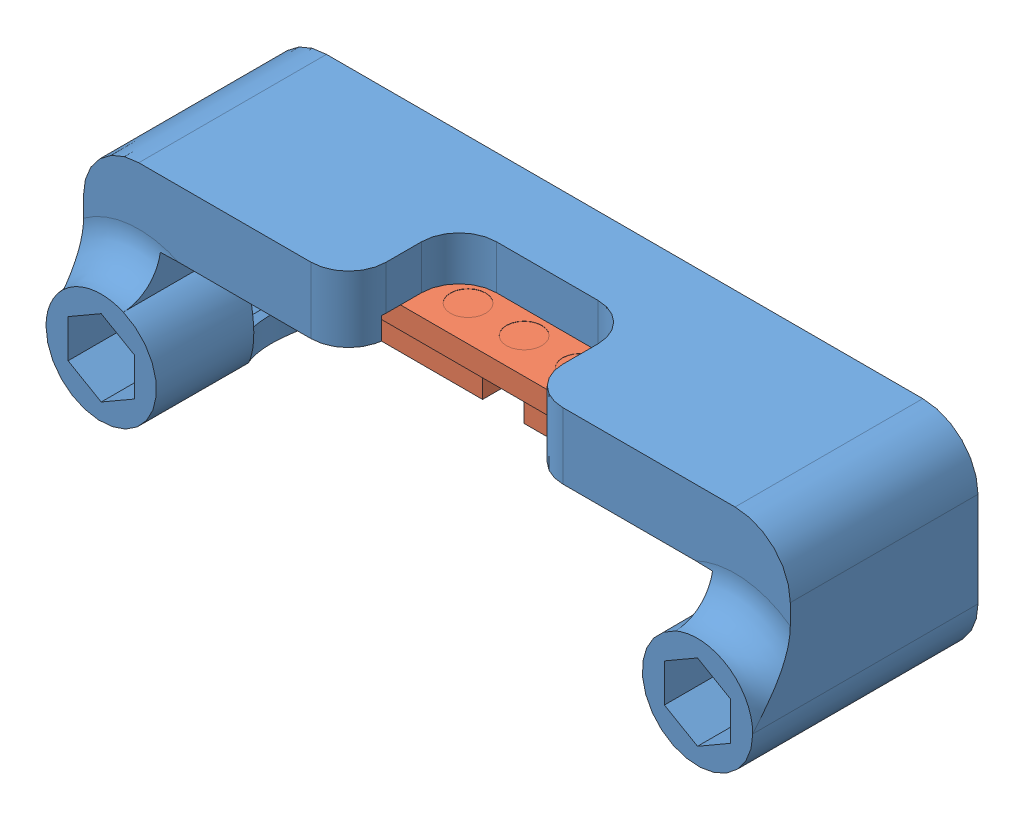
SolidWorks assembly led-bar-with-mount, configuration Default. Lengths in mm.
Overall size (32 9.3 10.45).
2 component instances, 2 part files, 3 mates.
Components (placement in the parent):
- led-bar-mount-1: led-bar-mount [Default] at origin size (32 9.3 10.45)
- led-bar-1: led-bar [Default] at (0 -33.425 3.075) x (-1 0 0) z (0 0 1) size (25 2.5 6.15)
Mates (geometry in assembly coordinates):
- Coincident1: coincident aligned: plane of led-bar-mount-1 through (0 0 0) normal (0 0 -1); plane of led-bar-1 through (12.5 -34.425 0) normal (0 0 -1)
- Coincident3: coincident anti-aligned: plane of led-bar-mount-1 through (0 -33.425 7) normal (0 -1 0); plane of led-bar-1 through (0 -33.425 3.075) normal (0 1 0)
- Width2: width aligned: plane of led-bar-mount-1 through (-12.5 0 7) normal (1 0 0); plane of led-bar-1 through (12.5 0 7) normal (-1 0 0); plane of led-bar-mount-1 through (12.5 -34.425 0) normal (1 0 0); plane of led-bar-1 through (-12.5 -34.425 0) normal (-1 0 0)
